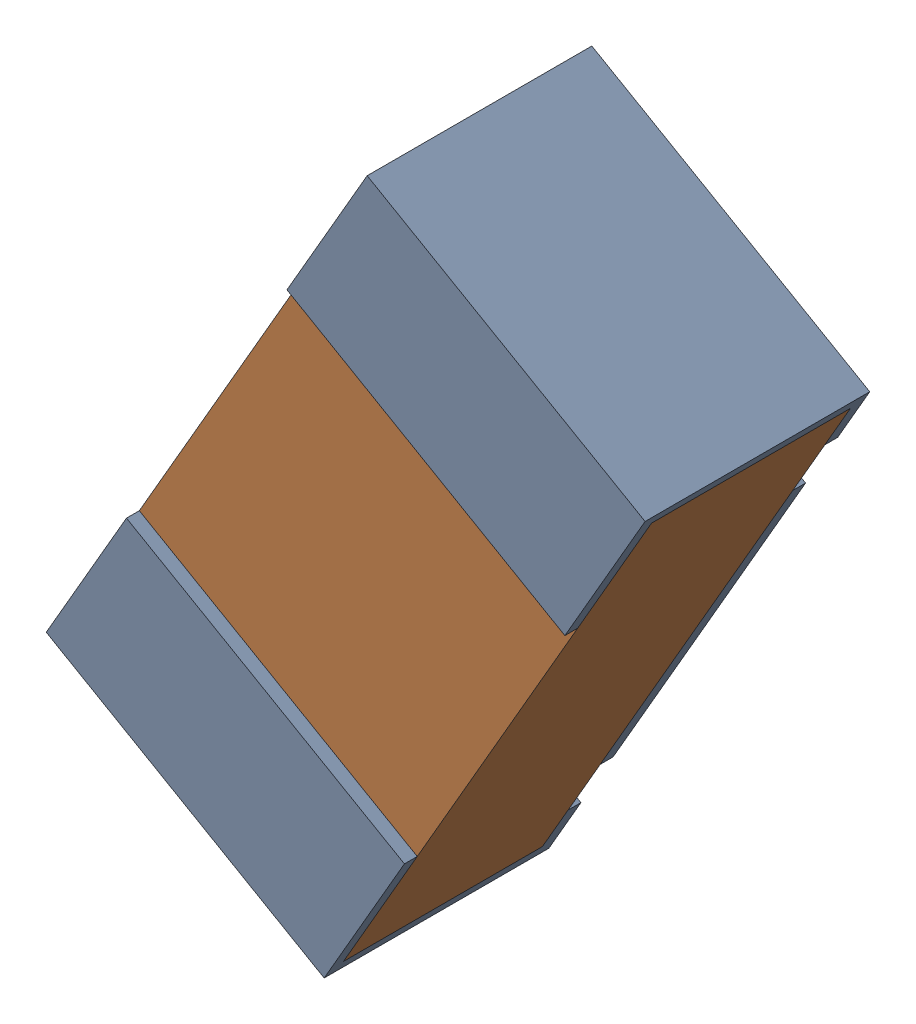
SolidWorks assembly R17, configuration Default. Lengths in mm.
Overall size (0.93 1.12 0.35).
3 component instances, 2 part files, 0 mates.
Components (placement in the parent):
- R17-subassembly-1-1: R17-subassembly-1 [Default] at (5.2461 -1.3729 -1.6307) x (-0.5 -0.866025 0) z (0.866025 -0.5 0) size (1 0.35 0.5)
  - 0402 resistor-1: 0402 resistor [Default] at origin size (1 0.35 0.5)
  - 0402 resistor-1-1: 0402 resistor-1 [Default] at origin size (0.96 0.31 0.5)
